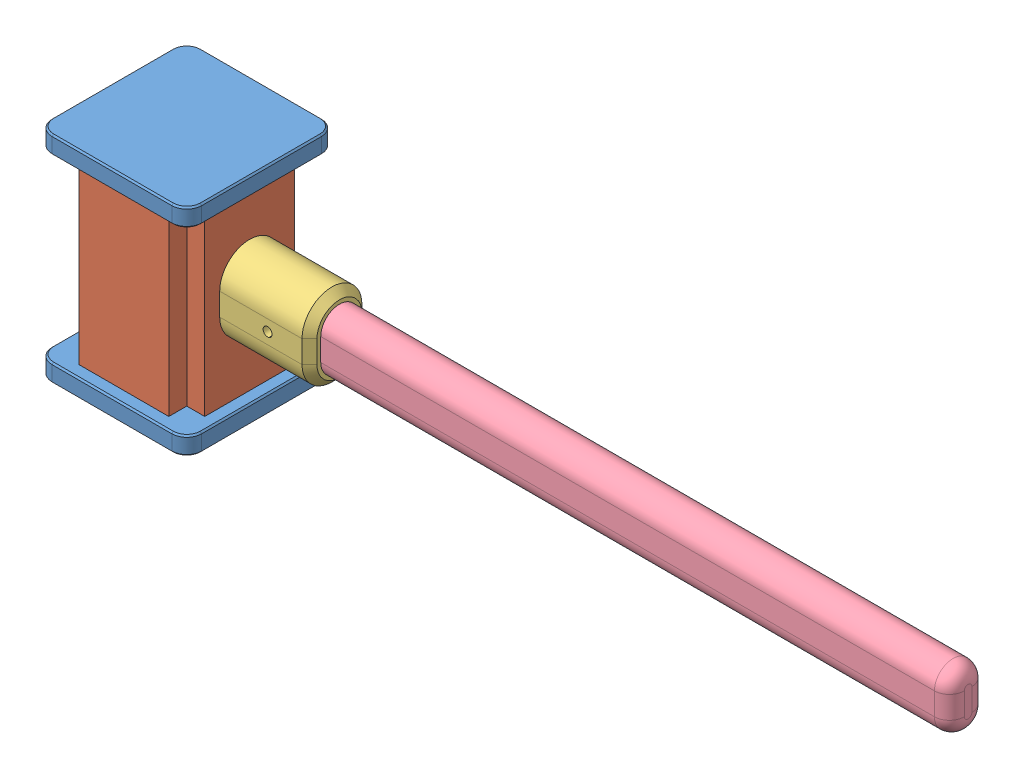
SolidWorks assembly Yucra_Fabrizio_E07, configuration Predeterminado. Lengths in mm.
Overall size (572 144 100).
8 component instances, 4 part files, 23 mates.
Components (placement in the parent):
- Yucra_Fabrizio_P59A-1: Yucra_Fabrizio_P59A [Predeterminado] at origin size (100 12 100)
- Yucra_Fabrizio_P59B-1: Yucra_Fabrizio_P59B [Predeterminado] at (0 72 42) size (60 120 12)
- Yucra_Fabrizio_P59B-2: Yucra_Fabrizio_P59B [Predeterminado] at (30 72 0) x (0 0 1) z (-1 0 0) size (60 120 12)
- Yucra_Fabrizio_P59B-3: Yucra_Fabrizio_P59B [Predeterminado] at (0 72 -30) size (60 120 12)
- Yucra_Fabrizio_P59B-4: Yucra_Fabrizio_P59B [Predeterminado] at (-30 72 0) x (0 0 -1) z (1 0 0) size (60 120 12)
- Yucra_Fabrizio_P59A-2: Yucra_Fabrizio_P59A [Predeterminado] at (0 132 0) size (100 12 100)
- Yucra_Fabrizio_P59C-1: Yucra_Fabrizio_P59C [Predeterminado] at (42 79.5 0) x (0 -1 0) z (0 0 1) size (55 60 40)
- Yucra_Fabrizio_P59D-1: Yucra_Fabrizio_P59D [Predeterminado] at (42 64.5 0) x (1 0 0) z (0 -1 0) size (480 25 40)
Mates (geometry in assembly coordinates):
- Coincidente1: coordinate: point of Yucra_Fabrizio_P59A-1
- Coincidente2: coincident anti-aligned: plane of Yucra_Fabrizio_P59A-1 through (-40 12 40) normal (0 1 0); plane of Yucra_Fabrizio_P59B-1 through (-30 12 30) normal (0 -1 0)
- Coincidente3: coincident aligned: line of Yucra_Fabrizio_P59B-1 through (-30 12 30) axis (1 0 0)
- Coincidente5: coincident: unknown of Yucra_Fabrizio_P59B-1
- Coincidente6: coincident anti-aligned: plane of Yucra_Fabrizio_P59A-1 through (-40 12 40) normal (0 1 0); plane of Yucra_Fabrizio_P59B-2 through (42 12 -30) normal (0 -1 0)
- Coincidente7: coincident anti-aligned: line of Yucra_Fabrizio_P59B-2 through (30 12 -30) axis (0 0 1)
- Coincidente8: coincident: unknown of Yucra_Fabrizio_P59B-2
- Coincidente9: coincident anti-aligned: plane of Yucra_Fabrizio_P59A-1 through (-40 12 40) normal (0 1 0); plane of Yucra_Fabrizio_P59B-3 through (-30 12 -42) normal (0 -1 0)
- Coincidente10: coincident aligned: line of Yucra_Fabrizio_P59B-3 through (-30 12 -30) axis (1 0 0)
- Coincidente11: coincident: unknown of Yucra_Fabrizio_P59B-3
- Coincidente12: coincident anti-aligned: plane of Yucra_Fabrizio_P59A-1 through (-40 12 40) normal (0 1 0); plane of Yucra_Fabrizio_P59B-4 through (-42 12 30) normal (0 -1 0)
- Coincidente13: coincident aligned: line of Yucra_Fabrizio_P59B-4 through (-30 12 30) axis (0 0 -1)
- Coincidente14: coincident: point of Yucra_Fabrizio_P59B-1; point of Yucra_Fabrizio_P59B-4
- Coincidente15: coincident anti-aligned: plane of Yucra_Fabrizio_P59B-1 through (-30 132 30) normal (0 1 0); plane of Yucra_Fabrizio_P59A-2 through (-40 132 40) normal (0 -1 0)
- Coincidente16: coincident aligned: plane of Yucra_Fabrizio_P59A-1 through (-50 12 40) normal (-1 0 0); plane of Yucra_Fabrizio_P59A-2 through (-50 144 40) normal (-1 0 0)
- Coincidente17: coincident aligned: plane of Yucra_Fabrizio_P59A-1 through (-40 12 50) normal (0 0 1); plane of Yucra_Fabrizio_P59A-2 through (-40 144 50) normal (0 0 1)
- Coincidente19: coincident: moEndPointRef_w of Yucra_Fabrizio_P59C-1
- Coincidente20: coincident: unknown of Yucra_Fabrizio_P59C-1
- Coincidente22: coincident anti-aligned: plane of Yucra_Fabrizio_P59B-2 through (42 72 0) normal (1 0 0); plane of Yucra_Fabrizio_P59C-1 through (42 79.5 0) normal (-1 0 0)
- Ancho2: width: cylinder of Yucra_Fabrizio_P59A-1; plane of Yucra_Fabrizio_P59C-1 through (-40 132 40) normal (0 -1 0); cylinder of Yucra_Fabrizio_P59A-2 through (74 72 -28.4853) axis (0 0 1) radius 3
- Coincidente23: coincident: plane of Yucra_Fabrizio_P59B-2 through (42 72 0) normal (1 0 0); plane of Yucra_Fabrizio_P59D-1 through (42 52.842 0) normal (-1 0 0)
- Coincidente24: coincident: plane of Yucra_Fabrizio_P59C-1 through (102 79.5 -12.5) normal (0 0 1); plane of Yucra_Fabrizio_P59D-1 through (522 64.5 -12.5) normal (0 0 -1)
- Concéntrica2: concentric aligned: cylinder of Yucra_Fabrizio_P59C-1 through (102 79.5 0) axis (-1 0 0) radius 12.5; cylinder of Yucra_Fabrizio_P59D-1 through (522 79.5 0) axis (-1 0 0) radius 12.5
